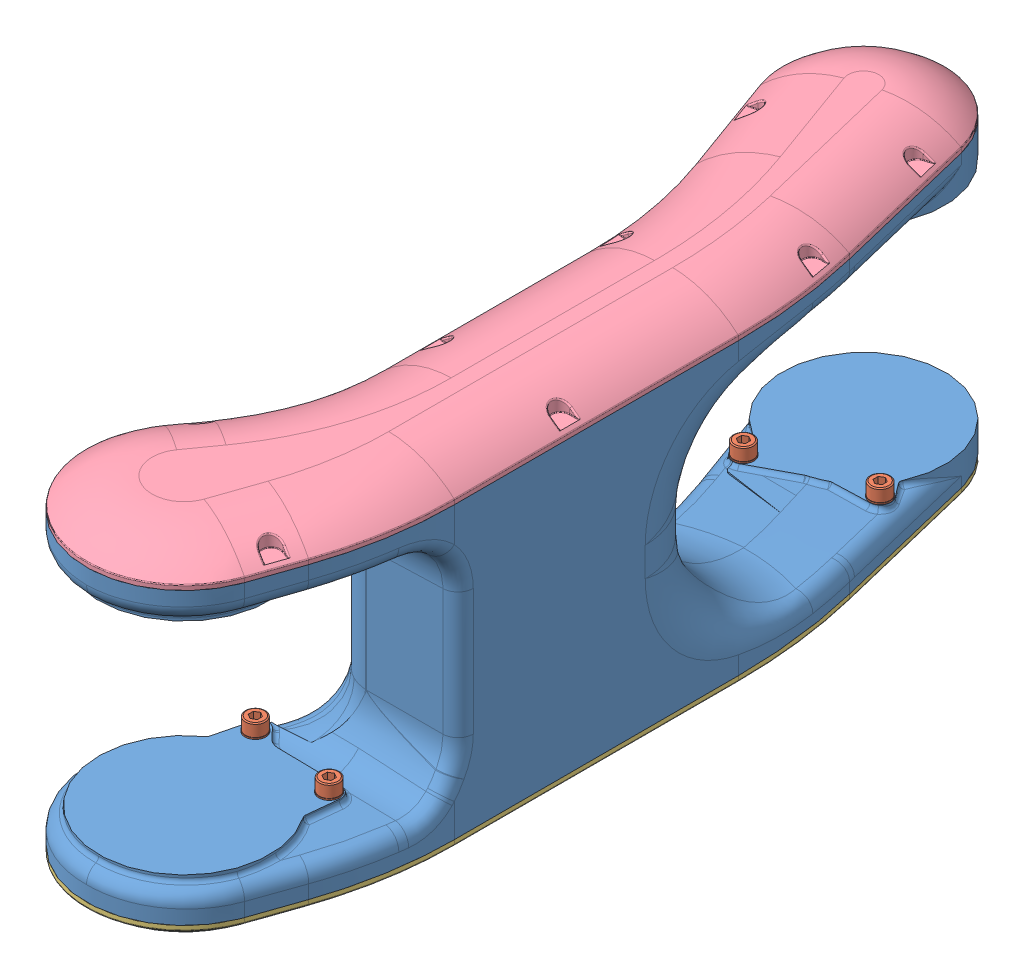
SolidWorks assembly GP7_L_AXIS, configuration Default. Lengths in mm.
Overall size (233.56 273.26 562.73).
7 component instances, 4 part files, 6 mates.
Components (placement in the parent):
- L_ARM-1: L_ARM [Default] at origin size (233.56 273.26 562.73)
- KU6BOLT_M8X16_SS_SSW-1: KU6BOLT_M8X16_SS_SSW [Default] at (39.9694 -71.1 -55.0132) size (13.5 24 13.5)
- KU6BOLT_M8X16_SS_SSW-7: KU6BOLT_M8X16_SS_SSW [Default] at (-18.4194 -74.1 -384.7528) size (13.5 24 13.5)
- KU6BOLT_M8X16_SS_SSW-6: KU6BOLT_M8X16_SS_SSW [Default] at (49.6447 -74.1 -406.2133) size (13.5 24 13.5)
- KU6BOLT_M8X16_SS_SSW-5: KU6BOLT_M8X16_SS_SSW [Default] at (-18.7433 -71.1 -65.3658) size (13.5 24 13.5)
- L_ARM_COVER-1: L_ARM_COVER [Default] at (0 -95 -222.5) x (-1 0 0) z (0 0 1) size (149 20 562)
- L_ARM_COVER2-2: L_ARM_COVER2 [Default] at (0 95 -222.5) x (-1 0 0) z (0 0 -1) size (149 20 562)
Mates (geometry in assembly coordinates):
- Concentric1: concentric anti-aligned: cylinder of HW1100931_L_ARM-1 through (-18.7433 -265.7349 -65.3658) axis (0 1 0) radius 7.5; cylinder of KU6BOLT_M8X16_SS_SSW-5 through (-18.7433 -61.9 -65.3658) axis (0 -1 0) radius 4
- Coincident1: coincident anti-aligned: plane of HW1100931_L_ARM-1 through (100 -72 -76.04) normal (0 1 0); plane of KU6BOLT_M8X16_SS_SSW-5 through (-18.7433 -72 -65.3658) normal (0 -1 0)
- Concentric2: concentric anti-aligned: cylinder of HW1100931_L_ARM-1 through (-18.4194 -240.2309 -384.7528) axis (0 1 0) radius 7; cylinder of KU6BOLT_M8X16_SS_SSW-7 through (-18.4194 -64.9 -384.7528) axis (0 -1 0) radius 4
- Coincident2: coincident anti-aligned: plane of HW1100931_L_ARM-1 through (0 -75 -445) normal (0 1 0); plane of KU6BOLT_M8X16_SS_SSW-7 through (-18.4194 -75 -384.7528) normal (0 -1 0)
- Concentric3: concentric anti-aligned: cylinder of HW1100931_L_ARM-1 through (49.6447 -240.2309 -406.2133) axis (0 1 0) radius 7; cylinder of KU6BOLT_M8X16_SS_SSW-6 through (49.6447 -64.9 -406.2133) axis (0 -1 0) radius 4
- Coincident3: coincident anti-aligned: plane of HW1100931_L_ARM-1 through (0 -75 -445) normal (0 1 0); plane of KU6BOLT_M8X16_SS_SSW-6 through (49.6447 -75 -406.2133) normal (0 -1 0)
